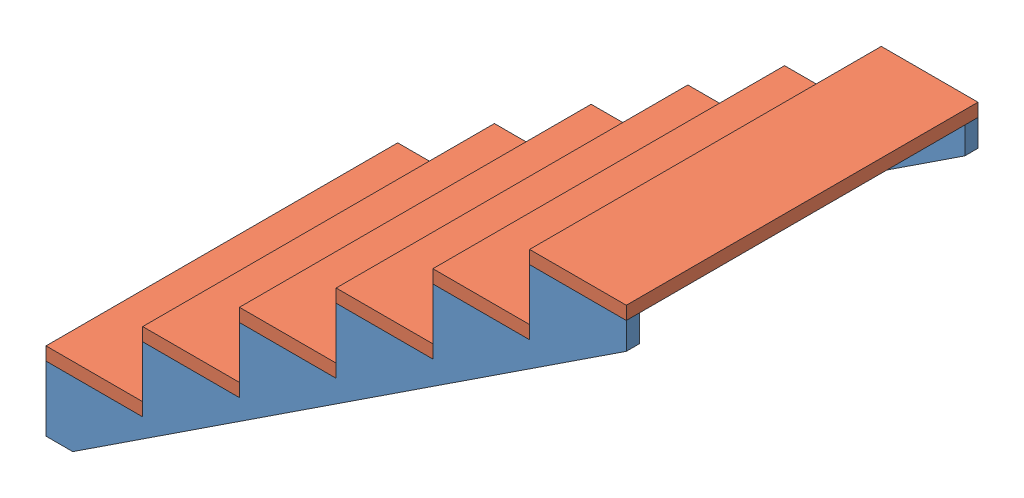
SolidWorks assembly Stairs Long, configuration Default. Lengths in mm.
Overall size (1676.4 1165.86 1016).
8 component instances, 2 part files, 21 mates.
Components (placement in the parent):
- Stairs Long-1: Stairs Long [Default] at origin size (1676.4 1127.76 38.1)
- Stairs Long-2: Stairs Long [Default] at (0 0 977.9) size (1676.4 1127.76 38.1)
- Stair Slab-1: Stair Slab [Default] at (139.7 226.06 508) x (0 0 -1) z (-1 0 0) size (1016 38.1 279.4)
- Stair Slab-2: Stair Slab [Default] at (698.5 601.98 508) x (0 0 -1) z (-1 0 0) size (1016 38.1 279.4)
- Stair Slab-3: Stair Slab [Default] at (977.9 789.94 508) x (0 0 -1) z (-1 0 0) size (1016 38.1 279.4)
- Stair Slab-4: Stair Slab [Default] at (419.1 375.92 508) x (0 0 -1) z (1 0 0) size (1016 38.1 279.4)
- Stair Slab-5: Stair Slab [Default] at (1257.3 977.9 508) x (0 0 1) z (1 0 0) size (1016 38.1 279.4)
- Stair Slab-6: Stair Slab [Default] at (1536.7 1127.76 508) x (0 0 -1) z (1 0 0) size (1016 38.1 279.4)
Mates (geometry in assembly coordinates):
- Coincident3: coincident anti-aligned: plane of Stairs Long-1 through (0 187.96 38.1) normal (0 1 0); plane of Stair Slab-1 through (139.7 187.96 508) normal (0 -1 0)
- Coincident5: coincident aligned: plane of Stairs Long-1 through (0 0 0) normal (0 0 -1); plane of Stair Slab-1 through (279.4 187.96 0) normal (0 0 -1)
- Coincident6: coincident aligned: plane of Stairs Long-1 through (0 187.96 38.1) normal (-1 0 0); plane of Stair Slab-1 through (0 187.96 1016) normal (-1 0 0)
- Coincident7: coincident anti-aligned: plane of Stairs Long-2 through (0 187.96 1016) normal (0 1 0); plane of Stair Slab-1 through (139.7 187.96 508) normal (0 -1 0)
- Coincident8: coincident aligned: plane of Stairs Long-2 through (0 187.96 1016) normal (-1 0 0); plane of Stair Slab-1 through (0 187.96 1016) normal (-1 0 0)
- Coincident9: coincident aligned: plane of Stairs Long-2 through (0 0 1016) normal (0 0 1); plane of Stair Slab-1 through (279.4 187.96 1016) normal (0 0 1)
- Coincident10: coincident aligned: plane of Stair Slab-4 through (279.4 414.02 1016) normal (0 0 1); plane of Stairs Long-2 through (0 0 1016) normal (0 0 1)
- Coincident11: coincident anti-aligned: plane of Stairs Long-2 through (279.4 375.92 1016) normal (0 1 0); plane of Stair Slab-4 through (419.1 375.92 508) normal (0 -1 0)
- Coincident12: coincident aligned: plane of Stairs Long-2 through (279.4 187.96 1016) normal (-1 0 0); plane of Stair Slab-4 through (279.4 414.02 1016) normal (-1 0 0)
- Coincident13: coincident aligned: plane of Stairs Long-1 through (558.8 375.92 38.1) normal (-1 0 0); plane of Stair Slab-2 through (558.8 563.88 1016) normal (-1 0 0)
- Coincident14: coincident anti-aligned: plane of Stairs Long-2 through (558.8 563.88 1016) normal (0 1 0); plane of Stair Slab-2 through (698.5 563.88 508) normal (0 -1 0)
- Coincident15: coincident aligned: plane of Stairs Long-2 through (0 0 1016) normal (0 0 1); plane of Stair Slab-2 through (838.2 563.88 1016) normal (0 0 1)
- Coincident16: coincident aligned: plane of Stairs Long-2 through (0 0 1016) normal (0 0 1); plane of Stair Slab-3 through (1117.6 751.84 1016) normal (0 0 1)
- Coincident17: coincident anti-aligned: plane of Stairs Long-2 through (838.2 751.84 1016) normal (0 1 0); plane of Stair Slab-3 through (977.9 751.84 508) normal (0 -1 0)
- Coincident18: coincident anti-aligned: plane of Stairs Long-2 through (1117.6 751.84 1016) normal (-1 0 0); plane of Stair Slab-3 through (1117.6 751.84 1016) normal (1 0 0)
- Coincident19: coincident anti-aligned: plane of Stairs Long-1 through (1397 939.8 38.1) normal (-1 0 0); plane of Stair Slab-5 through (1397 939.8 0) normal (1 0 0)
- Coincident20: coincident anti-aligned: plane of Stairs Long-2 through (1117.6 939.8 1016) normal (0 1 0); plane of Stair Slab-5 through (1257.3 939.8 508) normal (0 -1 0)
- Coincident21: coincident aligned: plane of Stairs Long-2 through (0 0 1016) normal (0 0 1); plane of Stair Slab-5 through (1117.6 939.8 1016) normal (0 0 1)
- Coincident22: coincident anti-aligned: plane of Stairs Long-2 through (1397 1127.76 1016) normal (0 1 0); plane of Stair Slab-6 through (1536.7 1127.76 508) normal (0 -1 0)
- Coincident23: coincident aligned: plane of Stairs Long-2 through (0 0 1016) normal (0 0 1); plane of Stair Slab-6 through (1397 1165.86 1016) normal (0 0 1)
- Coincident24: coincident: line of Stairs Long-2 through (1397 1127.76 977.9) axis (0 -1 0); plane of Stair Slab-6 through (1397 1165.86 1016) normal (-1 0 0)
